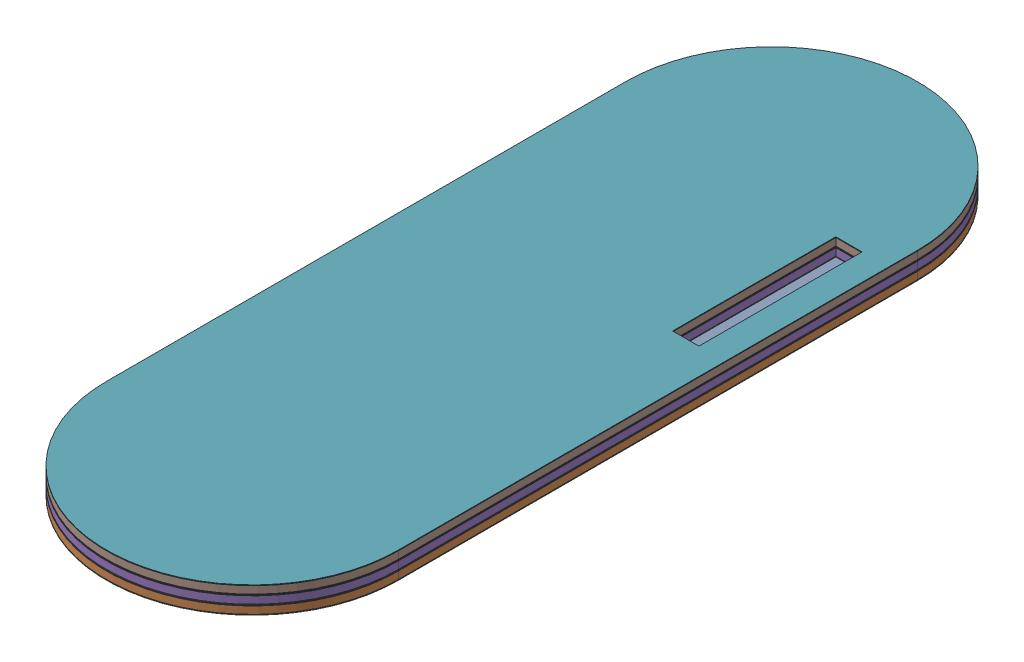
SolidWorks assembly Foot flat Left, configuration Default. Lengths in mm.
Overall size (100 9 277.8).
3 component instances, 2 part files, 6 mates.
Components (placement in the parent):
- Foot layer 3L-1: Foot layer 3L [Default] at (1053.3675 1053.983 1070.2043) size (100 3 277.8)
- Foot layer 1 and 2L-1: Foot layer 1 and 2L [Default] at (1053.3675 1056.983 1070.2043) size (100 3 277.8)
- Foot layer 1 and 2L-2: Foot layer 1 and 2L [Default] at (1053.3675 1059.983 1070.2043) size (100 3 277.8)
Mates (geometry in assembly coordinates):
- Coincident1: coincident anti-aligned: plane of Foot layer 3L-1 through (1053.3675 1056.983 981.3043) normal (0 1 0); plane of Foot layer 1 and 2L-1 through (1053.3675 1056.983 981.3043) normal (0 -1 0)
- Coincident2: coincident aligned: plane of Foot layer 3L-1 through (1103.3675 1056.733 1159.1043) normal (1 0 0); plane of Foot layer 1 and 2L-1 through (1103.3675 1059.733 1070.2043) normal (1 0 0)
- Coincident3: coincident: line of Foot layer 3L-1 through (1103.3675 1056.733 1159.1043) axis (0 -1 0); moEndPointRef_w of Foot layer 1 and 2L-1
- Coincident4: coincident anti-aligned: plane of Foot layer 1 and 2L-1 through (1053.3675 1059.983 1070.2043) normal (0 1 0); plane of Foot layer 1 and 2L-2 through (1053.3675 1059.983 981.3043) normal (0 -1 0)
- Coincident5: coincident aligned: plane of Foot layer 1 and 2L-1 through (1103.3675 1059.733 1070.2043) normal (1 0 0); plane of Foot layer 1 and 2L-2 through (1103.3675 1062.733 1070.2043) normal (1 0 0)
- Coincident6: coincident aligned: line of Foot layer 1 and 2L-1 through (1103.3675 1059.733 1159.1043) axis (0 -1 0); line of Foot layer 1 and 2L-2 through (1103.3675 1062.733 1159.1043) axis (0 -1 0)
